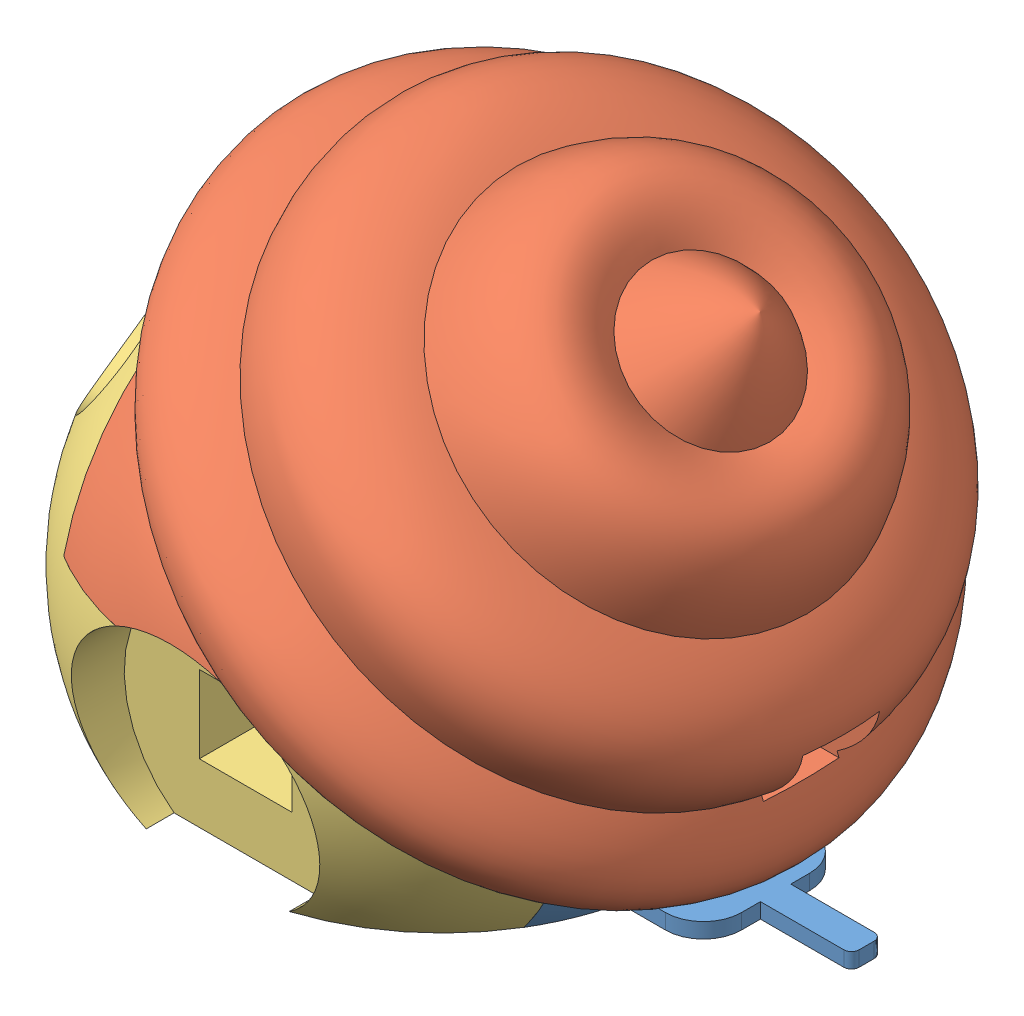
SolidWorks assembly 합체본(어셈블리), configuration 기본. Lengths in mm.
Overall size (95.23 80.54 94.52).
3 component instances, 3 part files, 6 mates.
Components (placement in the parent):
- 꼬리-3: 꼬리 [기본] at origin size (32 10 32)
- 머리_초코빵-2: 머리_초코빵 [기본] at (34.5632 -51.3462 -131.563) size (83.53 74.61 94.52)
- 아랫면-1: 아랫면 [기본] at (34.5632 -51.3462 -131.563) size (74 47 72.96)
Mates (geometry in assembly coordinates):
- 동심3: concentric aligned: cylinder of 머리_초코빵-2 through (47.6788 5.5 -44.9642) axis (0 1 0) radius 2; cylinder of 아랫면-1 through (47.6788 3 -44.9642) axis (0 1 0) radius 2.1
- 일치3: coincident anti-aligned: plane of 머리_초코빵-2 through (61.8065 27 -33.9325) normal (0 -1 0); plane of 아랫면-1 through (49.6842 27 -67.2202) normal (0 1 0)
- 동심4: concentric aligned: cylinder of 꼬리-3 through (28.71 -10 8.68) axis (0 -1 0) radius 1.9; cylinder of 아랫면-1 through (28.71 -10 8.68) axis (0 -1 0) radius 2
- 일치5: coincident anti-aligned: plane of 머리_초코빵-2 through (-19.0049 0 -37) normal (-1 0 0); plane of 아랫면-1 through (-19.0049 27 -37) normal (1 0 0)
- 일치6: coincident anti-aligned: plane of 꼬리-3 through (0 -13 0) normal (0 1 0); plane of 아랫면-1 through (36.9951 -13 -16) normal (0 -1 0)
- 일치7: coincident anti-aligned: plane of 꼬리-3 through (0 -13 16) normal (0 0 1); plane of 아랫면-1 through (7.9951 -13.17 16) normal (0 0 -1)
